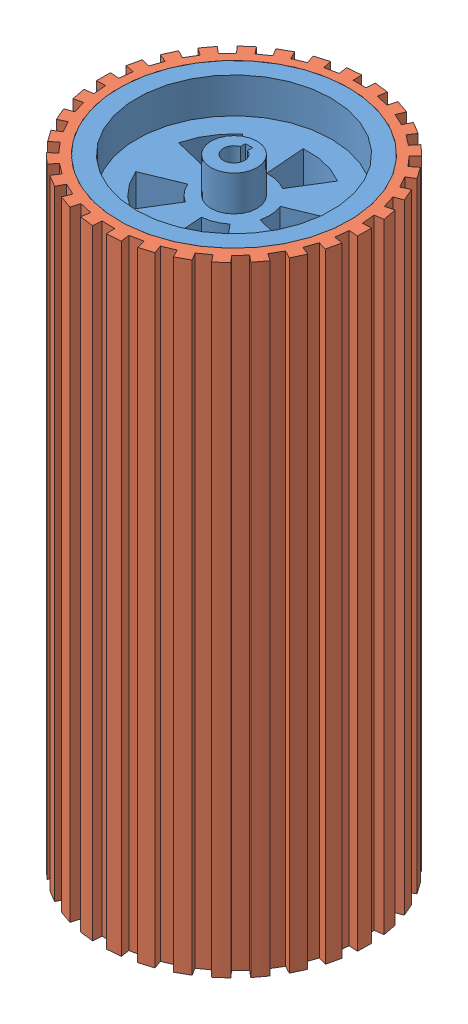
SolidWorks assembly Assem1, configuration Default. Lengths in mm.
Overall size (166.8 350 166.97).
2 component instances, 2 part files, 3 mates.
Components (placement in the parent):
- wheel rim-1: wheel rim [Default] at (102.1573 65.0647 363.573) size (130 350 130)
- wheel rubber-1: wheel rubber [Default] at (102.1573 65.0647 363.573) x (0.9927 0 0.120607) z (-0.120607 0 0.9927) size (149.8 350 150)
Mates (geometry in assembly coordinates):
- Concentric1: concentric: circle of wheel rim-1; circle of wheel rubber-1
- Coincident1: coincident: circle of wheel rim-1; circle of wheel rubber-1
- Lock1: lock: unknown of wheel rim-1; unknown of wheel rubber-1
